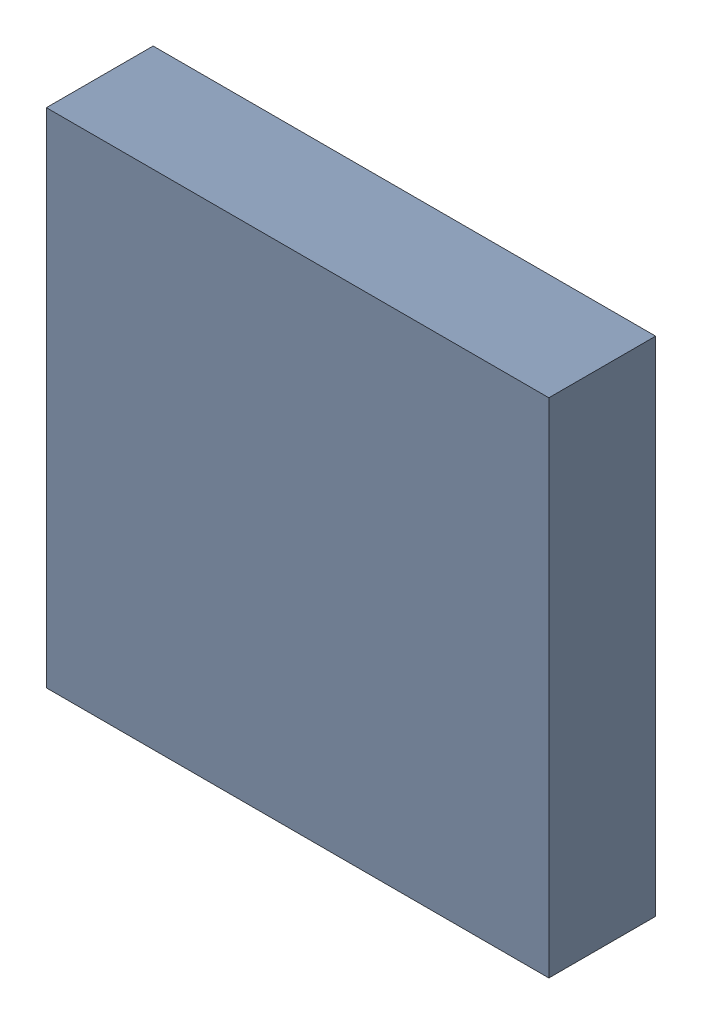
SolidWorks assembly IC3, configuration Standard. Lengths in mm.
Overall size (4 4 0.85).
2 component instances, 1 part files, 0 mates.
Components (placement in the parent):
- 668292984-1: 668292984 [Standard] at (8.35 -16.75 0) size (4 4 0.85)
  - Extruded_35-1: Extruded_35 [Standard] at origin size (4 4 0.85)
